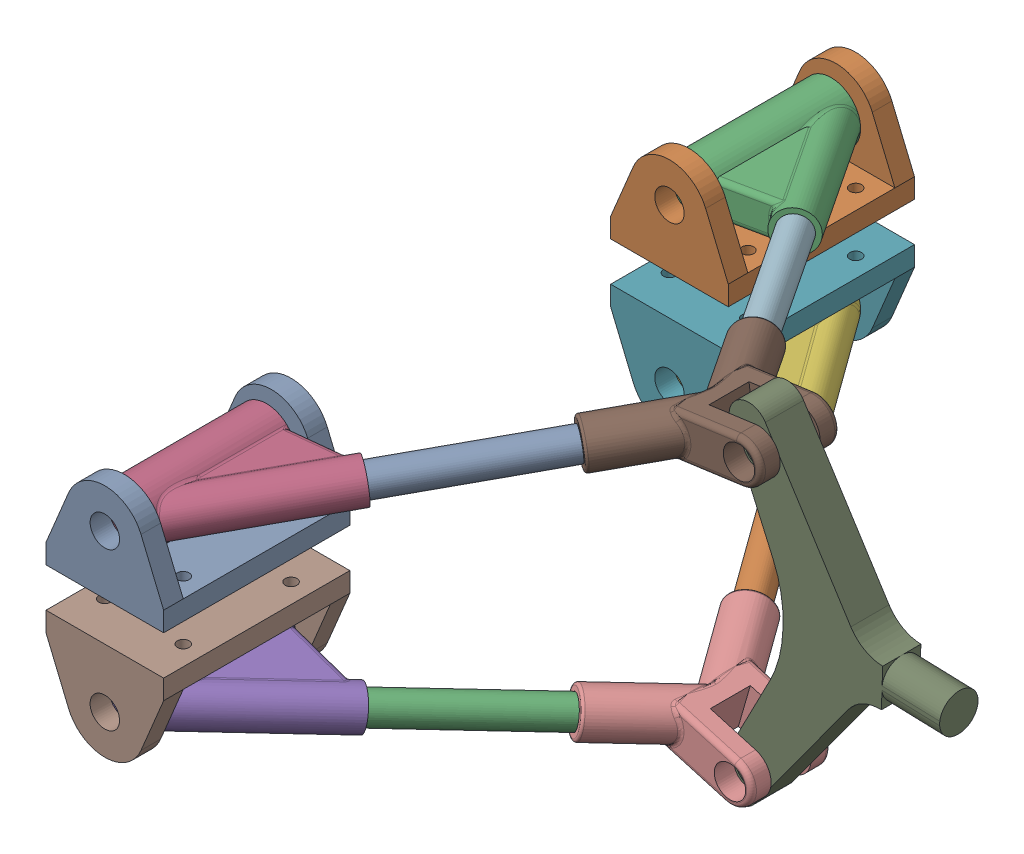
SolidWorks assembly steering_system, configuration Default. Lengths in mm.
Overall size (138.49 91.71 191.5).
15 component instances, 5 part files, 30 mates.
Components (placement in the parent):
- steer1-1: steer1 [Default] at (-90.2203 63.6989 68.6875) size (30 25 47.5)
- steer1-2: steer1 [Default] at (-90.2203 63.6989 -75.3172) size (30 25 47.5)
- steer2-1: steer2 [Default] at (-90.2203 63.6989 -57.8172) x (0 0 -1) z (-0.990708 -0.136007 0) size (37.8 15 37.24)
- steer2-2: steer2 [Default] at (-90.2203 63.6989 51.1875) x (0 0 1) z (-0.990708 -0.136007 0) size (37.8 15 37.24)
- steer2-3: steer2 [Default] at (-90.2203 23.6989 51.1875) x (0 0 1) z (-0.960812 0.277202 0) size (37.8 15 37.24)
- steer2-4: steer2 [Default] at (-90.2203 23.6989 -57.8172) x (0 0 -1) z (-0.962 0.273051 0) size (37.8 15 37.24)
- steer1-3: steer1 [Default] at (-90.2203 23.6989 -75.3172) x (1 0 0) z (0 0 -1) size (30 25 47.5)
- steer1-4: steer1 [Default] at (-90.2203 23.6989 68.6875) x (-1 0 0) z (0 0 1) size (30 25 47.5)
- steer3-1: steer3 [Default] at (-8.1456 38.0488 -3.3148) x (0 0 1) z (-0.999488 0.03199 0) size (9.75 90 55)
- steer4-1: steer4 [Default] at (-27.9645 5.7376 -3.3148) x (0 0 1) z (-0.960812 0.277202 0) size (50.78 11.67 38.23)
- steer4-2: steer4 [Default] at (-26.0273 72.5115 -3.3148) x (0 0 1) z (-0.990708 -0.136007 0) size (50.78 11.67 38.23)
- steer5-1: steer5 [Default] at (-79.4269 65.1807 -79.2519) x (0.820013 -0.136406 -0.555853) z (0.568247 0.07801 0.819152) size (7.45 7.45 75)
- steer5-2: steer5 [Default] at (-35.6441 71.1913 9.5075) x (0.022989 0.993602 0.110571) z (-0.568247 -0.07801 0.819152) size (7.45 7.45 75)
- steer5-3: steer5 [Default] at (-77.7491 20.1592 -76.2968) x (0.123641 -0.955993 -0.266063) z (0.55178 -0.156616 0.819152) size (7.45 7.45 75)
- steer5-4: steer5 [Default] at (-39.7691 9.1434 13.1908) x (0.089451 0.987279 -0.13145) z (-0.551099 0.158997 0.819152) size (7.45 7.45 75)
Mates (geometry in assembly coordinates):
- Concentric1: concentric anti-aligned: circle of steer1-1; circle of steer1-2
- Concentric2: concentric anti-aligned: cylinder of steer1-1 through (-90.2203 63.6989 92.4375) axis (0 0 -1) radius 3.75; cylinder of steer2-1 through (-90.2203 63.6989 -92.8172) axis (0 0 1) radius 5.125
- Width1: width anti-aligned: plane of steer2-1 through (-90.2203 63.6989 -92.8172) normal (0 0 -1); plane of steer1-2 through (-90.2203 63.6989 -57.8172) normal (0 0 1); plane of steer2-1 through (-105.2203 53.6989 -94.0672) normal (0 0 1); plane of steer1-2 through (-105.2203 53.6989 -56.5672) normal (0 0 -1)
- Concentric3: concentric aligned: cylinder of steer1-1 through (-90.2203 63.6989 92.4375) axis (0 0 -1) radius 3.75; cylinder of steer2-2 through (-90.2203 63.6989 86.1875) axis (0 0 -1) radius 5.125
- Width2: width anti-aligned: plane of steer2-2 through (-90.2203 63.6989 86.1875) normal (0 0 1); plane of steer1-1 through (-90.2203 63.6989 51.1875) normal (0 0 -1); plane of steer2-2 through (-90.2203 63.6989 44.9375) normal (0 0 -1); plane of steer1-1 through (-90.2203 63.6989 92.4375) normal (0 0 1)
- Coincident1: coincident aligned: plane of steer1-1 through (-90.2203 63.6989 44.9375) normal (0 0 -1); plane of steer1-4 through (-90.2203 23.6989 44.9375) normal (0 0 -1)
- Parallel1: parallel anti-aligned: plane of steer1-1 through (-90.2203 48.6989 68.6875) normal (0 -1 0); plane of steer1-4 through (-90.2203 38.6989 68.6875) normal (0 1 0)
- Coincident2: coincident aligned: plane of steer1-1 through (-75.2203 48.6989 44.9375) normal (1 0 0); plane of steer1-4 through (-75.2203 38.6989 92.4375) normal (1 0 0)
- Distance2: distance = 10 mm anti-aligned: plane of steer1-1 through (-90.2203 48.6989 68.6875) normal (0 -1 0); plane of steer1-4 through (-90.2203 38.6989 68.6875) normal (0 1 0)
- Parallel2: parallel anti-aligned: plane of steer1-2 through (-90.2203 48.6989 -75.3172) normal (0 -1 0); plane of steer1-3 through (-90.2203 38.6989 -75.3172) normal (0 1 0)
- Parallel3: parallel aligned: plane of steer1-2 through (-90.2203 63.6989 -99.0672) normal (0 0 -1); plane of steer1-3 through (-90.2203 23.6989 -99.0672) normal (0 0 -1)
- Coincident3: coincident aligned: plane of steer1-2 through (-90.2203 63.6989 -99.0672) normal (0 0 -1); plane of steer1-3 through (-90.2203 23.6989 -99.0672) normal (0 0 -1)
- Coincident4: coincident aligned: plane of steer1-2 through (-75.2203 48.6989 -99.0672) normal (1 0 0); plane of steer1-3 through (-75.2203 38.6989 -51.5672) normal (1 0 0)
- Coincident5: coincident aligned: plane of steer1-1 through (-75.2203 48.6989 44.9375) normal (1 0 0); plane of steer1-2 through (-75.2203 48.6989 -99.0672) normal (1 0 0)
- Distance3: distance = 10 mm anti-aligned: plane of steer1-2 through (-90.2203 48.6989 -75.3172) normal (0 -1 0); plane of steer1-3 through (-90.2203 38.6989 -75.3172) normal (0 1 0)
- Concentric4: concentric anti-aligned: cylinder of steer2-3 through (-90.2203 23.6989 86.1875) axis (0 0 -1) radius 5.125; circle of steer1-4
- Width3: width anti-aligned: plane of steer2-3 through (-90.2203 23.6989 86.1875) normal (0 0 1); plane of steer1-4 through (-90.2203 23.6989 51.1875) normal (0 0 -1); plane of steer2-3 through (-90.2203 23.6989 44.9375) normal (0 0 -1); plane of steer1-4 through (-90.2203 23.6989 92.4375) normal (0 0 1)
- Concentric6: concentric anti-aligned: cylinder of steer2-4 through (-90.2203 23.6989 -92.8172) axis (0 0 1) radius 5.125; circle of steer1-3
- Width4: width aligned: plane of steer2-4 through (-90.2203 23.6989 -57.8172) normal (0 0 1); plane of steer1-3 through (-90.2203 23.6989 -92.8172) normal (0 0 -1); plane of steer2-4 through (-90.2203 23.6989 -51.5672) normal (0 0 1); plane of steer1-3 through (-90.2203 23.6989 -99.0672) normal (0 0 -1)
- Concentric7: concentric aligned: cylinder of steer2-1 through (-64.8155 67.1866 -58.1889) axis (-0.568247 -0.07801 -0.819152) radius 5; cylinder of steer4-2 through (-25.2984 72.6116 -1.2233) axis (-0.568247 -0.07801 -0.819152) radius 5.5
- Concentric9: concentric aligned: cylinder of steer2-2 through (-64.8155 67.1866 51.5593) axis (-0.568247 -0.07801 0.819152) radius 5; cylinder of steer4-2 through (-25.2984 72.6116 -5.4064) axis (-0.568247 -0.07801 0.819152) radius 5.5
- Concentric10: concentric aligned: cylinder of steer2-3 through (-65.5822 16.5906 51.5593) axis (-0.551099 0.158997 0.819152) radius 5; cylinder of steer4-1 through (-27.2575 5.5337 -5.4064) axis (-0.551099 0.158997 0.819152) radius 5.5
- Concentric12: concentric aligned: circle of steer3-1; cylinder of steer4-2 through (-14.1388 74.1436 -13.4148) axis (0 0 1) radius 4
- Concentric13: concentric aligned: cylinder of steer3-1 through (-16.4347 2.4112 -8.1898) axis (0 0 1) radius 3.75; cylinder of steer4-1 through (-16.4347 2.4112 -13.4148) axis (0 0 1) radius 4
- Width5: width aligned: plane of steer3-1 through (-16.8609 78.3483 1.5602) normal (0 0 1); plane of steer4-2 through (-16.8609 78.3483 -8.1898) normal (0 0 -1); plane of steer3-1 through (-26.7754 77.9604 -8.4148) normal (0 0 1); plane of steer4-2 through (-26.7754 77.9604 1.7852) normal (0 0 -1)
- Width6: width anti-aligned: plane of steer3-1 through (-16.8609 78.3483 -8.1898) normal (0 0 -1); plane of steer4-1 through (-16.8609 78.3483 1.5602) normal (0 0 1); plane of steer3-1 through (-26.4399 11.0221 -8.4148) normal (0 0 1); plane of steer4-1 through (-26.4399 11.0221 1.7852) normal (0 0 -1)
- Concentric16: concentric anti-aligned: cylinder of steer4-1 through (-27.2575 5.5337 -5.4064) axis (-0.551099 0.158997 0.819152) radius 5.5; cylinder of steer5-4 through (-81.1015 21.0681 74.6272) axis (0.551099 -0.158997 -0.819152) radius 3.725
- Concentric17: concentric aligned: cylinder of steer2-1 through (-64.8155 67.1866 -58.1889) axis (-0.568247 -0.07801 -0.819152) radius 5; cylinder of steer5-1 through (-36.8084 71.0315 -17.8155) axis (-0.568247 -0.07801 -0.819152) radius 3.725
- Concentric18: concentric anti-aligned: cylinder of steer4-2 through (-25.2984 72.6116 -5.4064) axis (-0.568247 -0.07801 0.819152) radius 5.5; cylinder of steer5-2 through (-78.2626 65.3405 70.9439) axis (0.568247 0.07801 -0.819152) radius 3.725
- Concentric19: concentric anti-aligned: circle of steer2-4; cylinder of steer5-3 through (-36.3656 8.413 -14.8604) axis (-0.55178 0.156616 -0.819152) radius 3.725
